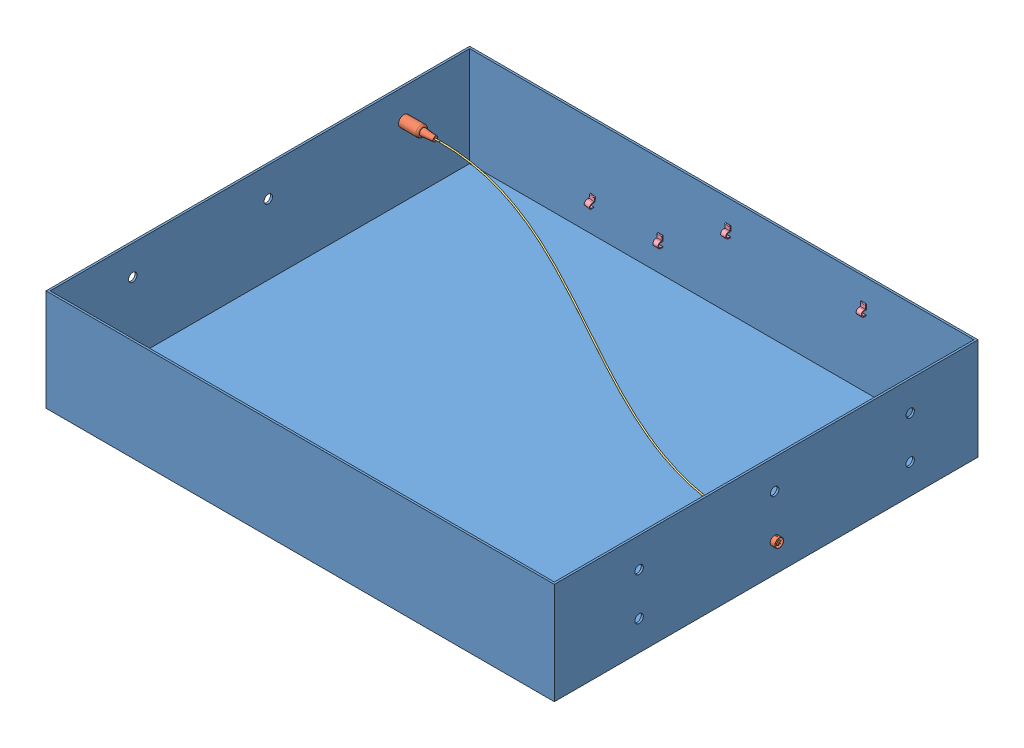
SolidWorks assembly top_assy, configuration Default. Lengths in mm.
Overall size (775.72 152.4 636.6).
9 component instances, 4 part files, 8 mates.
Components (placement in the parent):
- electronic housing-1: electronic housing [Default] at origin size (762 152.4 635)
- Harness_2-top_assy-1: Harness_2-top_assy [Default] at origin size (775.72 79.76 219.46)
  - plug-5pindin-1: plug-5pindin [Default] at (-476.25 107.95 -406.4) x (0 0 1) z (-1 0 0) size (16.26 16.26 67.02)
  - plug-5pindin-2: plug-5pindin [Default] at (222.25 44.45 -203.2) x (0 0 -1) z (1 0 0) size (16.26 16.26 67.02)
  - Cable^Harness_2-top_assy-1: Cable^Harness_2-top_assy [Default] at origin size (661.67 65.5 205.2) (virtual)
- 90_richco_hurc-4-01-clip-2: 90_richco_hurc-4-01-clip [Default] at (-117.348 107.4 -501.752) x (1 0 0) z (0 -1 0) size (7.62 12.25 15.7)
- 90_richco_hurc-4-01-clip-3: 90_richco_hurc-4-01-clip [Default] at (-218.9557 43.9 -501.752) x (0.999999 -0.001113 0) z (-0.001113 -0.999999 0) size (7.62 12.25 15.7)
- 90_richco_hurc-4-01-clip-4: 90_richco_hurc-4-01-clip [Default] at (85.852 107.4 -501.752) x (1 0 0) z (0 -1 0) size (7.62 12.25 15.7)
- 90_richco_hurc-4-01-clip-5: 90_richco_hurc-4-01-clip [Default] at (-321.7971 44.014 -501.752) x (0.983477 -0.181032 0) z (-0.181032 -0.983477 0) size (7.62 12.25 15.7)
Mates (geometry in assembly coordinates):
- Concentric41: concentric aligned: cylinder of electronic housing-1 through (-117.348 114.3 -468.376) axis (0 0 -1) radius 1.524; cylinder of 90_richco_hurc-4-01-clip-2 through (-117.348 114.3 -504.952) axis (0 0 -1) radius 1.5
- Coincident41: coincident anti-aligned: plane of electronic housing-1 through (-508 152.4 -504.952) normal (0 0 1); plane of 90_richco_hurc-4-01-clip-2 through (-121.148 110.6 -504.952) normal (0 0 -1)
- Concentric51: concentric aligned: cylinder of electronic housing-1 through (-218.948 50.8 -468.376) axis (0 0 -1) radius 1.524; cylinder of 90_richco_hurc-4-01-clip-3 through (-218.948 50.8 -504.952) axis (0 0 -1) radius 1.5
- Coincident51: coincident anti-aligned: plane of electronic housing-1 through (-508 152.4 -504.952) normal (0 0 1); plane of 90_richco_hurc-4-01-clip-3 through (-222.7521 47.1042 -504.952) normal (0 0 -1)
- Concentric61: concentric aligned: cylinder of electronic housing-1 through (85.852 114.3 -468.376) axis (0 0 -1) radius 1.524; cylinder of 90_richco_hurc-4-01-clip-4 through (85.852 114.3 -504.952) axis (0 0 -1) radius 1.5
- Coincident61: coincident anti-aligned: plane of electronic housing-1 through (-508 152.4 -504.952) normal (0 0 1); plane of 90_richco_hurc-4-01-clip-4 through (82.052 110.6 -504.952) normal (0 0 -1)
- Concentric71: concentric aligned: cylinder of electronic housing-1 through (-320.548 50.8 -468.376) axis (0 0 -1) radius 1.524; cylinder of 90_richco_hurc-4-01-clip-5 through (-320.548 50.8 -504.952) axis (0 0 -1) radius 1.5
- Coincident71: coincident anti-aligned: plane of electronic housing-1 through (-508 152.4 -504.952) normal (0 0 1); plane of 90_richco_hurc-4-01-clip-5 through (-324.955 47.8491 -504.952) normal (0 0 -1)
